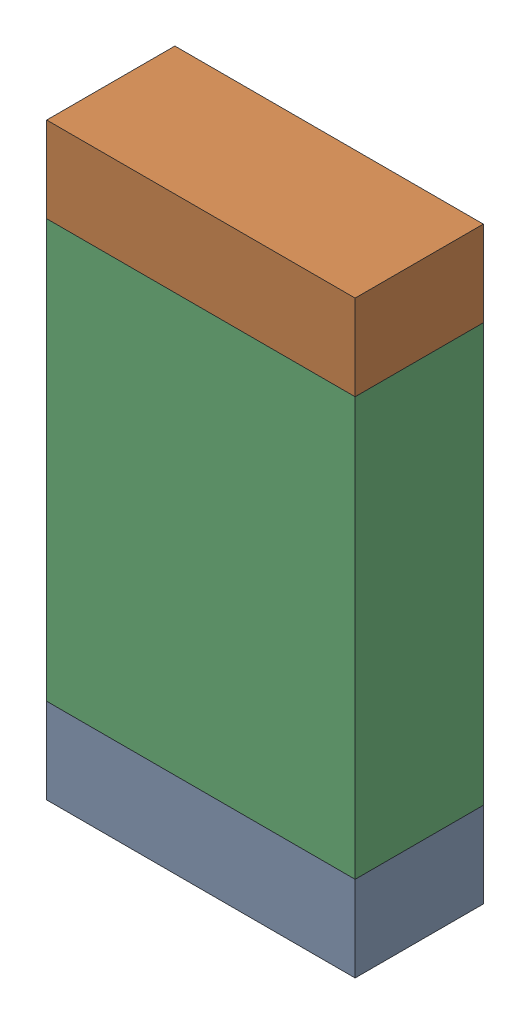
SolidWorks assembly R13, configuration Default. Lengths in mm.
Overall size (0.55 1.05 0.23).
6 component instances, 2 part files, 0 mates.
Components (placement in the parent):
- 822503136-1: 822503136 [Default] at (35.8206 5.2257 0.0254) size (0.55 0.15 0.23)
  - Extruded_13-1: Extruded_13 [Default] at origin size (0.55 0.15 0.23)
- 822503136-2: 822503136 [Default] at (35.8206 6.1233 0.0254) size (0.55 0.15 0.23)
  - Extruded_13-1: Extruded_13 [Default] at origin size (0.55 0.15 0.23)
- 822503272-1: 822503272 [Default] at (35.8206 5.6745 0.0254) size (0.55 0.75 0.23)
  - Extruded_14-1: Extruded_14 [Default] at origin size (0.55 0.75 0.23)
